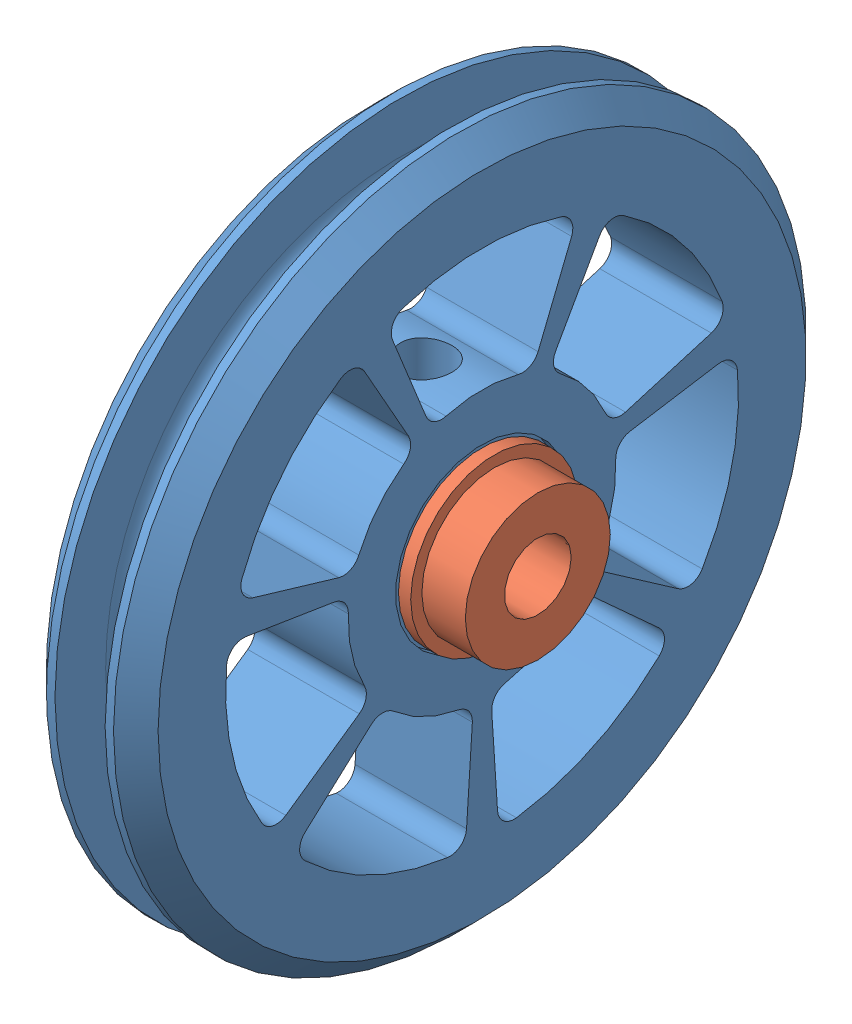
SolidWorks assembly Assemblage motorisation, configuration Default. Lengths in mm.
Overall size (20 62.1 62.1).
3 component instances, 2 part files, 6 mates.
Components (placement in the parent):
- galet moteur-1: galet moteur [Défaut] at origin size (10 62.1 62.1)
- Roulement F686ZZ-1: Roulement F686ZZ [Default] at (-5 0 0) x (-1 0 0) z (0 0 -1) size (5 15 15)
- Roulement F686ZZ-2: Roulement F686ZZ [Default] at (5 0 0) x (1 0 0) z (0 0 -1) size (5 15 15)
Mates (geometry in assembly coordinates):
- Coaxiale1: concentric anti-aligned: cylinder of Roulement F686ZZ-1 through (-5 0 0) axis (1 0 0) radius 6.5; cylinder of Roulement F686ZZ-2 through (5 0 0) axis (-1 0 0) radius 6.5
- Coaxiale2: concentric anti-aligned: cylinder of galet moteur-1 through (-19.0828 0 0) axis (-1 0 0) radius 3.05; cylinder of Roulement F686ZZ-1 through (-5 0 0) axis (1 0 0) radius 6.5
- Coïncidente1: coincident anti-aligned: plane of galet moteur-1 through (-5 29.05 0) normal (-1 0 0); plane of Roulement F686ZZ-1 through (-5 0 3) normal (1 0 0)
- Coïncidente2: coincident anti-aligned: plane of galet moteur-1 through (5 29.05 0) normal (1 0 0); plane of Roulement F686ZZ-2 through (5 0 3) normal (-1 0 0)
- Coïncidente6: coincident anti-aligned: plane of galet moteur-1 through (0 0 0) normal (0 0 1); plane of Roulement F686ZZ-1 through (-5 0 0) normal (0 0 -1)
- Coïncidente7: coincident aligned: plane of Roulement F686ZZ-1 through (-5 0 0) normal (0 0 -1); plane of Roulement F686ZZ-2 through (5 0 0) normal (0 0 -1)
